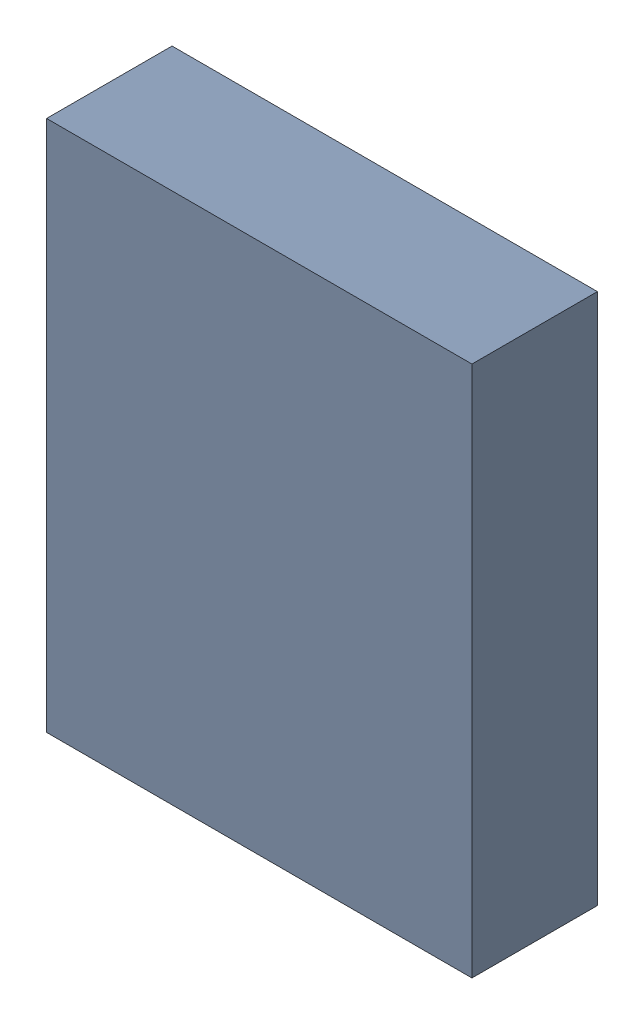
SolidWorks assembly L2, configuration Default. Lengths in mm.
Overall size (1 1.25 0.29).
2 component instances, 1 part files, 0 mates.
Components (placement in the parent):
- 870940800-1: 870940800 [Default] at (35.166 29.531 0.005) size (1 1.25 0.29)
  - Extruded_16-1: Extruded_16 [Default] at origin size (1 1.25 0.29)
